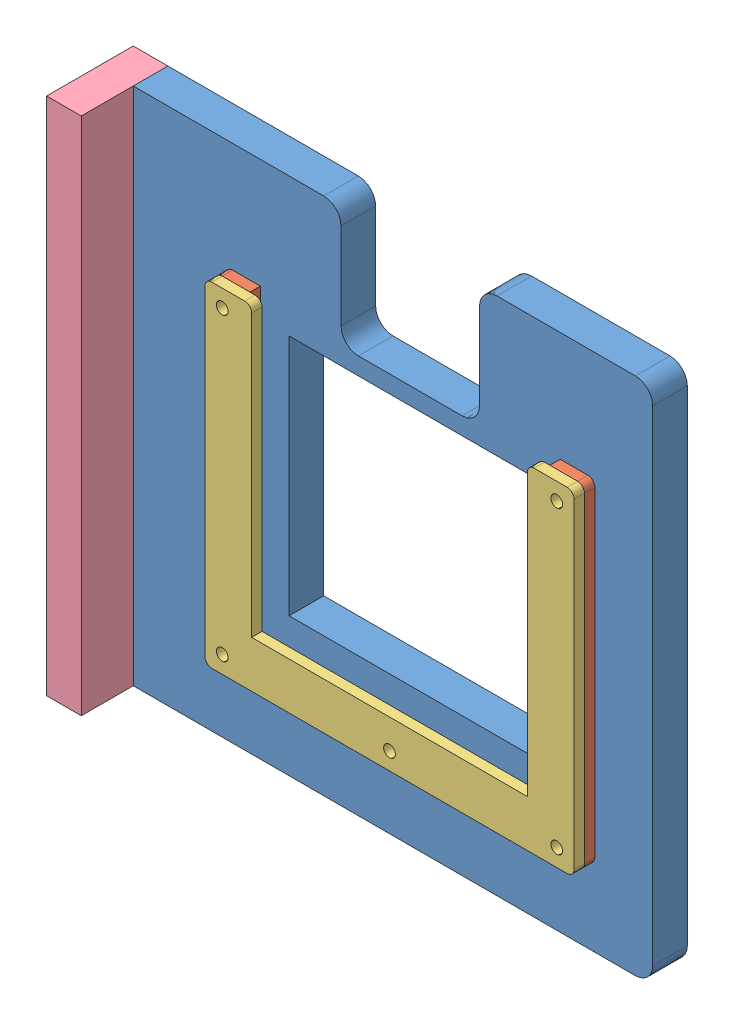
SolidWorks assembly 片弓, configuration 默认. Lengths in mm.
Overall size (160 150 25).
4 component instances, 4 part files, 12 mates.
Components (placement in the parent):
- 背板^片弓-1: 背板^片弓 [默认] at origin size (150 150 10) (virtual)
- 间隔层^片弓-1: 间隔层^片弓 [默认] at (0 0 10) size (106.6 96.6 3) (virtual)
- 片夹档板^片弓-1: 片夹档板^片弓 [默认] at (0 0 13) size (106.6 96.6 3) (virtual)
- 手柄^片弓-1: 手柄^片弓 [默认] at (-0.8453 0 0) x (0 0 1) z (-1 0 0) size (25 150 10) (virtual)
Mates (geometry in assembly coordinates):
- 在位1: in place: plane of 背板^片弓-1 through (0 0 10) normal (0 0 1); plane of 间隔层^片弓-1 through (0 0 10) normal (0 0 1); moOrthogonalPlaneRef_w of 背板^片弓-1 through (0 0 10) normal (0 0 1); plane of 间隔层^片弓-1 through (0 0 10) normal (0 1 0); plane of 背板^片弓-1 through (0 0 10) normal (0 0 1); plane of 间隔层^片弓-1 through (0 0 10) normal (1 0 0); plane of 背板^片弓-1 through (0 0 10) normal (0 0 1); unknown of 间隔层^片弓-1
- 重合1: coincident: plane of 背板^片弓-1; plane of 间隔层^片弓-1
- 重合2: coincident: moOrthogonalPlaneRef_w of 背板^片弓-1 through (0 0 10) normal (0 1 0); plane of 间隔层^片弓-1 through (0 0 10) normal (0 1 0)
- 重合3: coincident: moOrthogonalPlaneRef_w of 背板^片弓-1 through (0 0 10) normal (-1 0 0); plane of 间隔层^片弓-1 through (0 0 10) normal (1 0 0)
- 在位2: in place: plane of 间隔层^片弓-1 through (0 0 13) normal (0 0 1); plane of 片夹档板^片弓-1 through (0 0 13) normal (0 0 1); plane of 间隔层^片弓-1 through (0 0 13) normal (0 0 1); plane of 片夹档板^片弓-1 through (0 0 13) normal (0 1 0); plane of 间隔层^片弓-1 through (0 0 13) normal (0 0 1); plane of 片夹档板^片弓-1 through (0 0 13) normal (1 0 0); plane of 间隔层^片弓-1 through (0 0 13) normal (0 0 1); unknown of 片夹档板^片弓-1
- 重合4: coincident: plane of 间隔层^片弓-1; plane of 片夹档板^片弓-1
- 重合5: coincident: moOrthogonalPlaneRef_w of 间隔层^片弓-1 through (0 0 13) normal (0 1 0); plane of 片夹档板^片弓-1 through (0 0 13) normal (0 1 0)
- 重合6: coincident: moOrthogonalPlaneRef_w of 间隔层^片弓-1 through (0 0 13) normal (-1 0 0); plane of 片夹档板^片弓-1 through (0 0 13) normal (1 0 0)
- 在位3: in place: plane of 背板^片弓-1 through (0 0 10) normal (-1 0 0); plane of ? through (0 0 0) normal (-1 0 0); plane of 背板^片弓-1 through (0 0 10) normal (-1 0 0); plane of ? through (0 0 0) normal (0 1 0); plane of 背板^片弓-1 through (0 0 10) normal (-1 0 0); plane of ? through (0 0 0) normal (0 0 1); plane of 背板^片弓-1 through (-0.8453 0 10) normal (-1 0 0); unknown of 手柄^片弓-1
- 重合7: coincident: plane of 背板^片弓-1; plane of 手柄^片弓-1
- 重合8: coincident: moOrthogonalPlaneRef_w of 背板^片弓-1 through (-0.8453 0 0) normal (0 1 0); plane of 手柄^片弓-1 through (-0.8453 0 0) normal (0 1 0)
- 重合9: coincident: moOrthogonalPlaneRef_w of 背板^片弓-1 through (-0.8453 0 0) normal (0 0 -1); plane of 手柄^片弓-1 through (-0.8453 0 0) normal (0 0 1)
